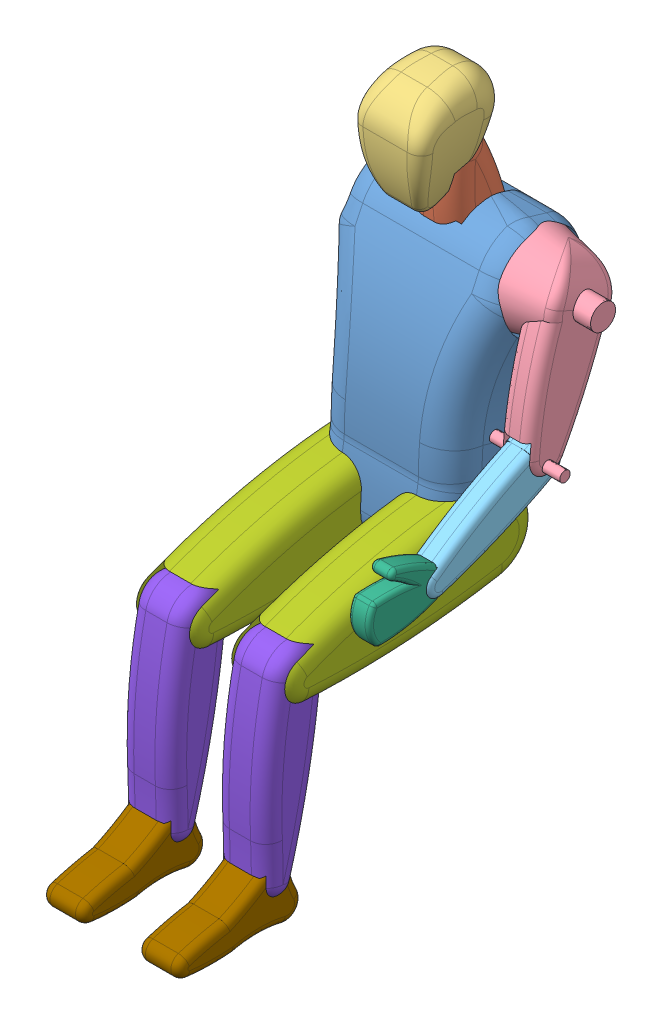
SolidWorks assembly robot1, configuration Default. Lengths in mm.
Overall size (504.8 1471.42 1009.25).
12 component instances, 9 part files, 20 mates.
Components (placement in the parent):
- Kropp-1: Kropp [Default] at (0 134.9016 -54.2254) x (1 0 0) z (0 0.282961 0.959132) size (422.35 711.41 261.74)
- Nacke-1: Nacke [Default] at (0 161.978 -136.3916) x (-1 0 0) z (0 0.085159 -0.996367) size (127 303.69 155.57)
- Huvud-1: Huvud [Default] at (0 148.3787 -127.8083) x (1 0 0) z (0 -0.239303 0.970945) size (171.5 248.6 227.81)
- ╓verarm-1: ╓verarm [Default] at (-0.1 145.8359 -27.7726) x (1 0 0) z (0 0.421808 0.906685) size (128.62 422.65 206.39)
- Underarm-1: Underarm [Default] at (-0.1 110.3178 -75.0894) x (1 0 0) z (0 0.859675 0.510841) size (65.65 357.53 110.91)
- Hand-1: Hand [Default] at (0 -10.7287 -127.5596) x (1 0 0) z (0 0.985346 0.170567) size (59.04 197.95 139.28)
- Lσr-4: Lσr [Default] at (0.1 -206.3128 -309.3147) x (-1 0 0) z (0 -1 0) size (152.4 600.65 232.31)
- Smalben-3: Smalben [Default] at (0.1 525.2363 470.5608) x (-1 0 0) z (0 0 -1) size (127 495.02 154.58)
- Fot-3: Fot [Default] at (-228.7 525.2363 522.3923) size (103.89 141.47 296.74)
- Fot-4: Fot [Default] at (0.1 525.2363 522.3923) size (103.89 141.47 296.74)
- Smalben-4: Smalben [Default] at (228.5 525.2363 470.5608) x (-1 0 0) z (0 0 -1) size (127 495.02 154.58)
- Lσr-5: Lσr [Default] at (228.5 -206.3128 -309.3147) x (-1 0 0) z (0 -1 0) size (152.4 600.65 232.31)
Mates (geometry in assembly coordinates):
- Concentric1: concentric aligned: cylinder of Kropp-1 through (-211.1781 -166.8461 -6.3529) axis (1 0 0) radius 105; cylinder of Lσr-4 through (-190.4 -166.8461 -6.3529) axis (1 0 0) radius 101.6
- Coincident2: coincident aligned: plane of Kropp-1 through (0 134.9016 -54.2254) normal (1 0 0)
- Coincident4: coincident anti-aligned: plane of Kropp-1 through (-38 -166.8461 -6.3529) normal (-1 0 0); plane of Lσr-4 through (-38 -109.5104 484.9018) normal (1 0 0)
- Parallel1: parallel anti-aligned: plane of Lσr-4 through (0.1 -206.3128 -309.3147) normal (0 -1 0)
- Concentric2: concentric anti-aligned: cylinder of Lσr-4 through (-50.7 -230.4761 446.3976) axis (-1 0 0) radius 63.5; cylinder of Smalben-3 through (-177.7 -230.4761 446.3976) axis (1 0 0) radius 63.5
- Coincident5: coincident anti-aligned: plane of Lσr-4 through (-177.7 -230.4761 446.3976) normal (1 0 0); plane of Smalben-3 through (-177.7 -655.2119 503.1673) normal (-1 0 0)
- Parallel2: parallel anti-aligned: plane of Smalben-3 through (0.1 525.2363 470.5608) normal (0 0 -1)
- Concentric3: concentric aligned: cylinder of Smalben-3 through (-63.2 -633.7788 496.4765) axis (-1 0 0) radius 38.5; cylinder of Fot-3 through (-63.6 -633.7788 496.4765) axis (-1 0 0) radius 38.1
- Coincident6: coincident anti-aligned: plane of Smalben-3 through (-165.2 -633.7788 496.4765) normal (1 0 0); plane of Fot-3 through (-165.2 -721.8533 443.678) normal (-1 0 0)
- Parallel3: parallel aligned: plane of Fot-3 through (-228.7 525.2363 522.3923) normal (0 1 0)
- Concentric4: concentric aligned: cylinder of Kropp-1 through (-63.5 353.532 -114.0583) axis (1 0 0) radius 76.5; cylinder of Nacke-1 through (-63.5 353.532 -114.0583) axis (1 0 0) radius 76.2
- Coincident9: coincident anti-aligned: plane of Kropp-1 through (-63.5 353.532 -114.0583) normal (1 0 0); plane of Nacke-1 through (-63.5 315.5293 -85.9774) normal (-1 0 0)
- Concentric5: concentric aligned: cylinder of Nacke-1 through (-63.5 527.8818 -79.2012) axis (1 0 0) radius 50.8; cylinder of Huvud-1 through (-63.5 527.8818 -79.2012) axis (1 0 0) radius 51
- Coincident10: coincident anti-aligned: plane of Nacke-1 through (-63.5 315.5293 -85.9774) normal (-1 0 0); plane of Huvud-1 through (-63.5 527.8818 -79.2012) normal (1 0 0)
- Concentric7: concentric aligned: cylinder of Kropp-1 through (215.9013 318.1032 -114.4658) axis (-1 0 0) radius 103.5; circle of ╓verarm-1
- Coincident12: coincident anti-aligned: plane of Kropp-1 through (165 318.1032 -114.4658) normal (1 0 0); plane of ╓verarm-1 through (165 263.0628 36.337) normal (-1 0 0)
- Concentric8: concentric anti-aligned: cylinder of ╓verarm-1 through (334 32.3426 -23.1371) axis (-1 0 0) radius 12.5; cylinder of Underarm-1 through (222.1487 32.3426 -23.1371) axis (1 0 0) radius 12.5
- Coincident13: coincident anti-aligned: plane of ╓verarm-1 through (222.15 52.1449 -28.8471) normal (1 0 0); plane of Underarm-1 through (222.15 -155.8073 224.273) normal (-1 0 0)
- Concentric9: concentric anti-aligned: cylinder of Underarm-1 through (228.4 -92.4566 226.842) axis (1 0 0) radius 34; cylinder of Hand-1 through (279.4 -92.4566 226.842) axis (-1 0 0) radius 33.02
- Coincident14: coincident anti-aligned: plane of Underarm-1 through (279.4 -92.4566 226.842) normal (-1 0 0); plane of Hand-1 through (279.4 -31.5349 403.4705) normal (1 0 0)
